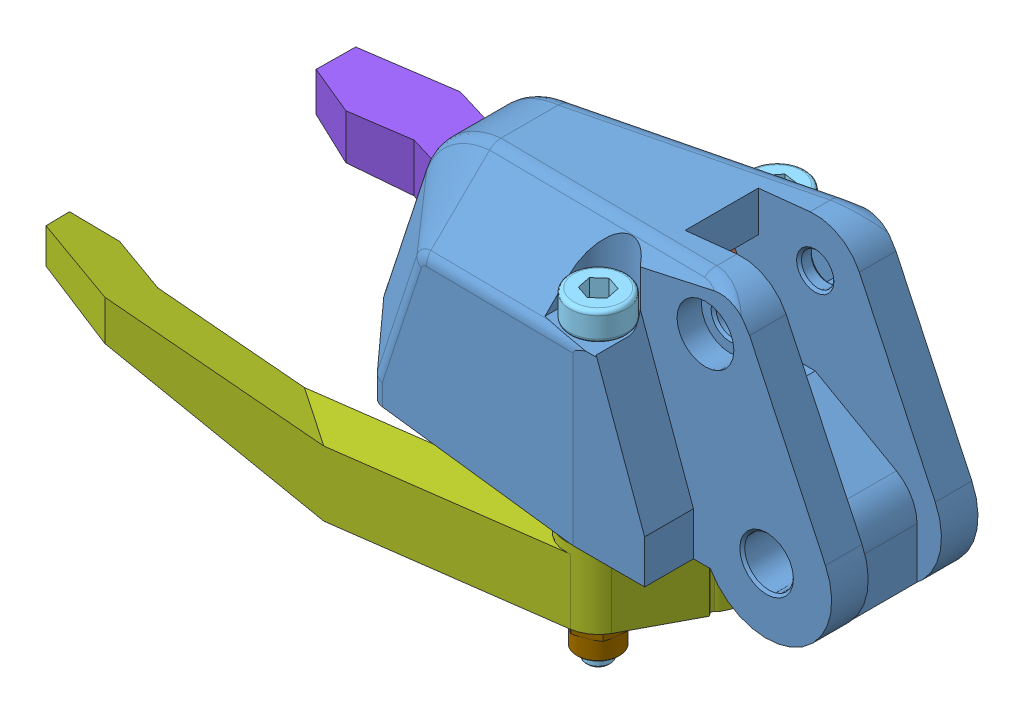
SolidWorks assembly 夹爪完全体, configuration 默认. Lengths in mm.
Overall size (88.43 45.17 61.98).
16 component instances, 13 part files, 28 mates.
Components (placement in the parent):
- 夹爪支架-1: 夹爪支架 [默认] at origin size (60.52 34.67 30)
- MG90S 金属舵机装配体 2018-1: MG90S 金属舵机装配体 2018 [默认] at (-29.5244 7.15 0) size (39.32 34.99 13.02) (flexible)
  - MG90S 金属舵机渲染2018-1: MG90S 金属舵机渲染2018 [默认] x (-1 0 0) z (0 0 -1) size (32.2 32.2 12.5)
  - cross recessed pan head screws gb(GB_CROSS_SCREWS_TYPE1 M2X4-4  H type-N)2018-1: cross recessed pan head screws gb(GB_CROSS_SCREWS_TYPE1 M2X4-4  H type-N)2018 [默认] at (-5.29 -23.85 0) x (0 1 0) z (-0.996226 0 -0.086793) size (5.59 4 4)
  - MG90S 金属舵机单舵臂渲染2018-1: MG90S 金属舵机单舵臂渲染2018 [默认] at (-5.29 -23.25 0) x (0.980774 0 0.195147) z (0 -1 0) size (21 6.8 4.7)
- ￠4×M3×30 轴肩螺丝 2018-1: ￠4×M3×30 轴肩螺丝 2018 [默认] at (-18.7132 17.5 11) x (0.980387 0 -0.197081) z (0.197081 0 0.980387) size (7 39.5 7)
- ￠4×M3×30 轴肩螺丝 2018-2: ￠4×M3×30 轴肩螺丝 2018 [默认] at (-18.7132 17.5 -11) x (0.92568 0 -0.378308) z (0.378308 0 0.92568) size (7 39.5 7)
- 主动齿-1: 主动齿 [M1X17] at (-34.8144 -16.1 0) x (-0.971356 0 0.237629) z (0 1 0) size (18.97 18.89 5)
- 上手指齿轮组合-1: 上手指齿轮组合 [默认] at (1.7867 0 3.863) x (0.980777 0 0.195134) z (-0.195134 0 0.980777) size (65.48 17.8 37.01)
- 下手指齿轮组合-1: 下手指齿轮组合 [默认] at (-3.2982 0 4.2827) x (0.968993 0 0.247087) z (-0.247087 0 0.968993) size (69.3 14.8 16)
- 上从动齿-1: 上从动齿 [M1X22] at (-18.7132 -5.1 11) x (-0.968993 0 0.247087) z (0 -1 0) size (24 23.85 11) (hidden)
- 下从动齿-1: 下从动齿 [M1X22] at (-18.7132 -5.1 -11) x (0.247087 0 -0.968993) z (0 -1 0) size (24 23.85 5) (hidden)
- 夹爪手指-1: 夹爪手指 [默认] at (-18.7132 -16.1 11) x (-0.968993 0 0.247087) z (0 -1 0) size (64 15 14.8) (hidden)
- 镜向夹爪手指-2: 镜向夹爪手指 [默认] at (-18.7132 -16.1 -11) x (-0.968993 0 -0.247087) z (0 1 0) size (64 15 14.8) (hidden)
- GB／T6172．2-2000非金属嵌件六角锁紧薄螺母3-3: GB／T6172．2-2000非金属嵌件六角锁紧薄螺母3 [默认] at (-18.7132 -13.1 -11) x (-0.949572 0 -0.31355) z (0 -1 0) size (13.56 6.01 3.9)
- GB／T6172．2-2000非金属嵌件六角锁紧薄螺母3-5: GB／T6172．2-2000非金属嵌件六角锁紧薄螺母3 [默认] at (-18.7132 -13.1 11) x (-0.991647 0 -0.12898) z (0 -1 0) size (13.56 6.01 3.9)
Mates (geometry in assembly coordinates):
- 重合1: coincident aligned: plane of MG90S 金属舵机装配体 2018-1 through (-29.5244 7.15 0) normal (0 0 1)
- 距离1: distance = 22 mm: plane of assembly; point of 夹爪支架-1; plane of MG90S 金属舵机装配体 2018-1 through (-29.5244 7.15 0) normal (1 0 0)
- 重合2: coincident aligned: plane of MG90S 金属舵机装配体 2018-1/MG90S 金属舵机渲染2018-1 through (-29.5244 0 -6.25) normal (0 1 0)
- 同心1: concentric anti-aligned: cylinder of 夹爪支架-1 through (-18.7132 26.6732 11) axis (0 -1 0) radius 2.1; cylinder of ￠4×M3×30 轴肩螺丝 2018-1 through (-18.7132 21 11) axis (0 1 0) radius 2
- 重合3: coincident anti-aligned: plane of 夹爪支架-1 through (-18.7132 17.5 11) normal (0 1 0); plane of ￠4×M3×30 轴肩螺丝 2018-1 through (-20.5269 17.5 11.3646) normal (0 -1 0)
- 同心2: concentric anti-aligned: cylinder of 夹爪支架-1 through (-18.7132 26.6732 -11) axis (0 -1 0) radius 2.1; cylinder of ￠4×M3×30 轴肩螺丝 2018-2 through (-18.7132 21 -11) axis (0 1 0) radius 2
- 重合4: coincident anti-aligned: plane of 夹爪支架-1 through (-18.7132 17.5 -11) normal (0 1 0); plane of ￠4×M3×30 轴肩螺丝 2018-2 through (-20.4257 17.5 -10.3001) normal (0 -1 0)
- 同心3: concentric anti-aligned: cylinder of MG90S 金属舵机装配体 2018-1/MG90S 金属舵机单舵臂渲染2018-1 through (-34.8144 -14.1 0) axis (0 -1 0) radius 3.4; line of 主动齿-1 through (-34.8144 -105.09 0) axis (0 1 0)
- 重合5: coincident aligned: plane of MG90S 金属舵机装配体 2018-1/MG90S 金属舵机单舵臂渲染2018-1 through (-34.8144 -16.1 0) normal (0 -1 0); plane of 主动齿-1 through (-34.8144 -16.1 0) normal (0 -1 0)
- 同心4: concentric anti-aligned: cylinder of ￠4×M3×30 轴肩螺丝 2018-1 through (-18.7132 21 11) axis (0 1 0) radius 2; line of 上从动齿-1 through (-18.7132 83.89 11) axis (0 -1 0)
- 重合6: coincident aligned: plane of 主动齿-1 through (-34.8144 -16.1 0) normal (0 -1 0); plane of 上从动齿-1 through (-18.7132 -16.1 11) normal (0 -1 0)
- 同心5: concentric anti-aligned: cylinder of ￠4×M3×30 轴肩螺丝 2018-2 through (-18.7132 21 -11) axis (0 1 0) radius 2; line of 下从动齿-1 through (-18.7132 83.89 -11) axis (0 -1 0)
- 重合8: coincident anti-aligned: plane of 上从动齿-1; plane of 下从动齿-1
- 齿轮配合1: gear = 24 : 24 mm: cylinder of 上从动齿-1 through (-18.7132 -16.1 11) axis (0 1 0) radius 12; cylinder of 下从动齿-1 through (-18.7132 -10.1 -11) axis (0 1 0) radius 12
- 重合10: coincident aligned: plane of 上从动齿-1 through (-18.7132 -5.1 11) normal (0 1 0); plane of 下从动齿-1 through (-18.7132 -5.1 -11) normal (0 1 0)
- 齿轮配合2: gear = 22 : 17 mm: cylinder of 主动齿-1 through (-34.8144 -11.1 0) axis (0 -1 0) radius 9.5; cylinder of 上从动齿-1 through (-18.7132 -16.1 11) axis (0 1 0) radius 12
- 在位1: in place: plane of ? through (-18.7132 -16.1 11) normal (0 -1 0); plane of ? through (0 -16.1 0) normal (0 -1 0); moOrthogonalPlaneRef_w of ? through (-18.7132 -16.1 11) normal (0 -1 0); plane of ? through (0 -16.1 0) normal (0 0 -1); plane of ? through (-18.7132 -16.1 11) normal (0 -1 0); plane of ? through (0 -16.1 0) normal (-1 0 0); plane of 上从动齿-1 through (-18.7132 -16.1 11) normal (0 -1 0); unknown of 夹爪手指-1
- 重合11: coincident aligned: plane of 上从动齿-1; plane of 夹爪手指-1
- 重合12: coincident aligned: moOrthogonalPlaneRef_w of 上从动齿-1; plane of 夹爪手指-1 through (-18.7132 -16.1 11) normal (-0.247087 0 -0.968993)
- 重合13: coincident anti-aligned: moOrthogonalPlaneRef_w of 上从动齿-1; plane of 夹爪手指-1 through (-18.7132 -16.1 11) normal (-0.968993 0 0.247087)
- LimitAngle1: limit planar angle = 0.249673 rad anti-aligned: plane of 上从动齿-1 through (-18.7132 -5.1 11) normal (-0.247087 0 -0.968993)
- 锁定1: lock: unknown of 上从动齿-1; unknown of 上手指齿轮组合-1
- 锁定2: lock: unknown of 下从动齿-1; unknown of 下手指齿轮组合-1
- 角度3: planar angle = 0.436332 rad aligned: plane of MG90S 金属舵机装配体 2018-1/MG90S 金属舵机单舵臂渲染2018-1 through (-34.8144 -16.1 0) normal (-0.195147 0 0.980774); plane of 主动齿-1 through (-34.8144 -16.1 0) normal (0.237629 0 0.971356)
- 同心6: concentric anti-aligned: cylinder of ￠4×M3×30 轴肩螺丝 2018-2 through (-18.7132 21 -11) axis (0 1 0) radius 1.5; cylinder of GB／T6172．2-2000非金属嵌件六角锁紧薄螺母3-3 through (-18.7132 -13.1 -11) axis (0 -1 0) radius 1.4286
- 重合14: coincident anti-aligned: plane of 下手指齿轮组合-1 through (-18.7132 -13.1 -11) normal (0 -1 0); plane of GB／T6172．2-2000非金属嵌件六角锁紧薄螺母3-3 through (-14.8287 -13.1 -14.4642) normal (0 1 0)
- 同心8: concentric anti-aligned: cylinder of ￠4×M3×30 轴肩螺丝 2018-1 through (-18.7132 21 11) axis (0 1 0) radius 1.5; cylinder of GB／T6172．2-2000非金属嵌件六角锁紧薄螺母3-5 through (-18.7132 -13.1 11) axis (0 -1 0) radius 1.4286
- 重合15: coincident anti-aligned: plane of 上手指齿轮组合-1 through (-18.7132 -13.1 11) normal (0 -1 0); plane of GB／T6172．2-2000非金属嵌件六角锁紧薄螺母3-5 through (-15.5512 -13.1 6.8658) normal (0 1 0)
